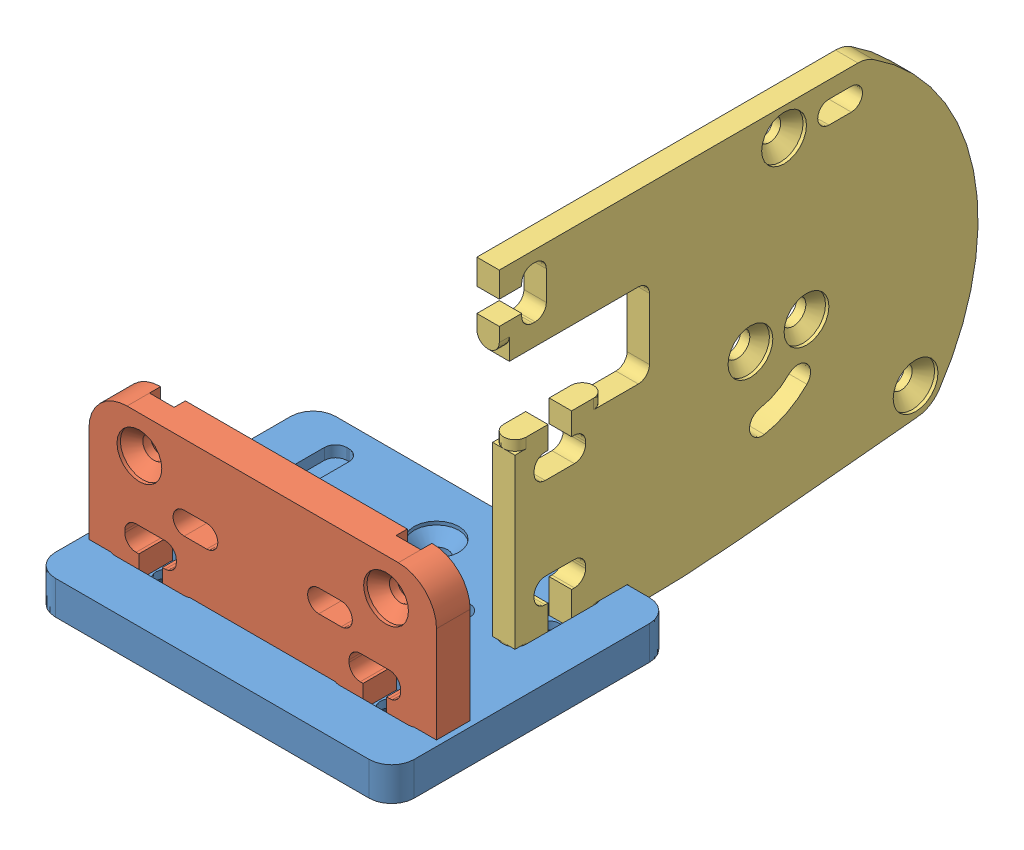
SolidWorks assembly test-joint, configuration Default. Lengths in mm.
Overall size (32 33 56.3).
3 component instances, 3 part files, 6 mates.
Components (placement in the parent):
- test-joint-1: test-joint [Default] at origin size (32 3 25)
- battery-stopper-1: battery-stopper [Default] at (0 9 5) size (31 12.9 3)
- camera-mount-1: camera-mount [Right] at (11 3 -23.5) x (-1 0 0) z (0 0 -1) size (2 32 42.7)
Mates (geometry in assembly coordinates):
- Width1: width aligned: plane of test-joint-1 through (-13.1 2 4.9) normal (0 0 1); plane of battery-stopper-1 through (-13.1 2 8.1) normal (0 0 -1); plane of test-joint-1 through (0 9 8) normal (0 0 1); plane of battery-stopper-1 through (0 9 5) normal (0 0 -1)
- Width2: width aligned: plane of test-joint-1 through (16 3 -12.5) normal (1 0 0); plane of battery-stopper-1 through (-16 3 -12.5) normal (-1 0 0); plane of test-joint-1 through (15.5 9 8) normal (1 0 0); plane of battery-stopper-1 through (-15.5 9 8) normal (-1 0 0)
- Coincident2: coincident anti-aligned: plane of test-joint-1 through (0 3 0) normal (0 1 0); plane of battery-stopper-1 through (0 3 8) normal (0 -1 0)
- Coincident3: coincident anti-aligned: plane of test-joint-1 through (0 3 0) normal (0 1 0); plane of camera-mount-1 through (10 3 -23.5) normal (0 -1 0)
- Width3: width anti-aligned: plane of test-joint-1 through (11.1 2 -10.6) normal (0 0 1); plane of camera-mount-1 through (11.1 2 -2.4) normal (0 0 -1); plane of test-joint-1 through (10 3 -4.2) normal (0 0 -1); plane of camera-mount-1 through (10 3 -8.8) normal (0 0 1)
- Width4: width aligned: plane of test-joint-1 through (9.9 2 -9.6) normal (1 0 0); plane of camera-mount-1 through (12.1 2 -9.6) normal (-1 0 0); plane of test-joint-1 through (12 3 -23.5) normal (1 0 0); plane of camera-mount-1 through (10 3 -23.5) normal (-1 0 0)
